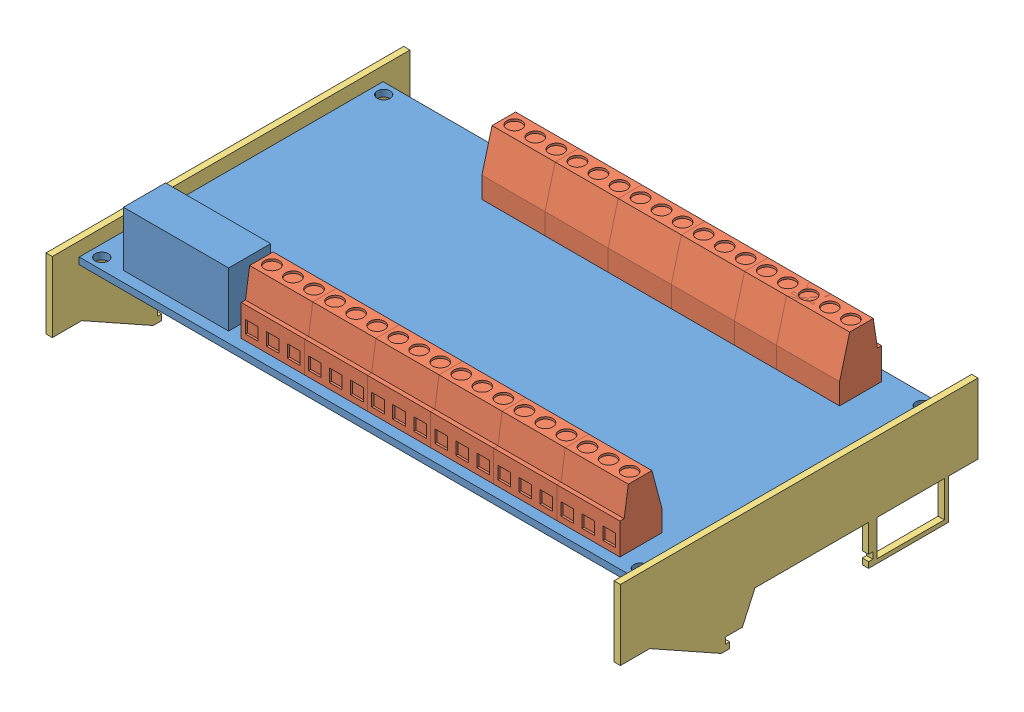
SolidWorks assembly Sanwo_16ch_mosfet_board, configuration Default. Lengths in mm.
Overall size (136.5 36.9 85).
15 component instances, 3 part files, 45 mates.
Components (placement in the parent):
- Sanwo_16ch_mosfet_board-1: Sanwo_16ch_mosfet_board [Default] at origin size (133.5 14.6 72.2)
- screw_terminal_3x_large-1: screw_terminal_3x_large [Default] at (73.5 1.6 -64.7) size (15 18 10)
- screw_terminal_3x_large-2: screw_terminal_3x_large [Default] at (103.5 1.6 -64.7) size (15 18 10)
- screw_terminal_3x_large-3: screw_terminal_3x_large [Default] at (88.5 1.6 -64.7) size (15 18 10)
- screw_terminal_3x_large-4: screw_terminal_3x_large [Default] at (58.5 1.6 -64.7) size (15 18 10)
- screw_terminal_3x_large-5: screw_terminal_3x_large [Default] at (113.5 1.6 -64.7) size (15 18 10)
- screw_terminal_3x_large-6: screw_terminal_3x_large [Default] at (43.5 1.6 -64.7) size (15 18 10)
- screw_terminal_3x_large-7: screw_terminal_3x_large [Default] at (43.5 1.6 -7.5) x (-1 0 0) z (0 0 -1) size (15 18 10)
- screw_terminal_3x_large-8: screw_terminal_3x_large [Default] at (103.5 1.6 -7.5) x (-1 0 0) z (0 0 -1) size (15 18 10)
- screw_terminal_3x_large-9: screw_terminal_3x_large [Default] at (118.5 1.6 -7.5) x (-1 0 0) z (0 0 -1) size (15 18 10)
- screw_terminal_3x_large-10: screw_terminal_3x_large [Default] at (73.5 1.6 -7.5) x (-1 0 0) z (0 0 -1) size (15 18 10)
- screw_terminal_3x_large-11: screw_terminal_3x_large [Default] at (58.5 1.6 -7.5) x (-1 0 0) z (0 0 -1) size (15 18 10)
- screw_terminal_3x_large-12: screw_terminal_3x_large [Default] at (88.5 1.6 -7.5) x (-1 0 0) z (0 0 -1) size (15 18 10)
- Sanwo_16ch_mosfet_board_DIN_rail_support-1: Sanwo_16ch_mosfet_board_DIN_rail_support [Default] at (0 -18.4 -36.1) x (0 0 1) z (-1 0 0) size (85 26.2 1.5)
- Sanwo_16ch_mosfet_board_DIN_rail_support-2: Sanwo_16ch_mosfet_board_DIN_rail_support [Default] at (135 -18.4 -36.1) x (0 0 1) z (-1 0 0) size (85 26.2 1.5)
Mates (geometry in assembly coordinates):
- Coincident12: coincident aligned: plane of screw_terminal_3x_large-7 through (43.5 1.6 -7.5) normal (0 -1 0); plane of screw_terminal_3x_large-8 through (103.5 1.6 -7.5) normal (0 -1 0)
- Coincident13: coincident aligned: plane of screw_terminal_3x_large-7 through (43.5 1.6 -7.5) normal (0 -1 0); plane of screw_terminal_3x_large-9 through (118.5 1.6 -7.5) normal (0 -1 0)
- Coincident14: coincident aligned: plane of screw_terminal_3x_large-7 through (43.5 1.6 -7.5) normal (0 -1 0); plane of screw_terminal_3x_large-10 through (73.5 1.6 -7.5) normal (0 -1 0)
- Coincident15: coincident aligned: plane of screw_terminal_3x_large-7 through (43.5 1.6 -7.5) normal (0 -1 0); plane of screw_terminal_3x_large-11 through (58.5 1.6 -7.5) normal (0 -1 0)
- Coincident16: coincident aligned: plane of screw_terminal_3x_large-7 through (43.5 1.6 -7.5) normal (0 -1 0); plane of screw_terminal_3x_large-12 through (88.5 1.6 -7.5) normal (0 -1 0)
- Coincident17: coincident aligned: plane of screw_terminal_3x_large-6 through (43.5 1.6 -64.7) normal (0 -1 0); plane of screw_terminal_3x_large-7 through (43.5 1.6 -7.5) normal (0 -1 0)
- Coincident18: coincident aligned: plane of screw_terminal_3x_large-5 through (113.5 1.6 -64.7) normal (0 -1 0); plane of screw_terminal_3x_large-7 through (43.5 1.6 -7.5) normal (0 -1 0)
- Coincident19: coincident aligned: plane of screw_terminal_3x_large-4 through (58.5 1.6 -64.7) normal (0 -1 0); plane of screw_terminal_3x_large-7 through (43.5 1.6 -7.5) normal (0 -1 0)
- Coincident20: coincident aligned: plane of screw_terminal_3x_large-3 through (88.5 1.6 -64.7) normal (0 -1 0); plane of screw_terminal_3x_large-7 through (43.5 1.6 -7.5) normal (0 -1 0)
- Coincident21: coincident aligned: plane of screw_terminal_3x_large-2 through (103.5 1.6 -64.7) normal (0 -1 0); plane of screw_terminal_3x_large-7 through (43.5 1.6 -7.5) normal (0 -1 0)
- Coincident22: coincident aligned: plane of screw_terminal_3x_large-1 through (73.5 1.6 -64.7) normal (0 -1 0); plane of screw_terminal_3x_large-7 through (43.5 1.6 -7.5) normal (0 -1 0)
- Coincident23: coincident anti-aligned: plane of Sanwo_16ch_mosfet_board-1 through (0 1.6 0) normal (0 1 0); plane of screw_terminal_3x_large-7 through (43.5 1.6 -7.5) normal (0 -1 0)
- Coincident24: coincident anti-aligned: plane of screw_terminal_3x_large-4 through (51 15.6 -69.7) normal (-1 0 0); plane of screw_terminal_3x_large-6 through (51 15.6 -69.7) normal (1 0 0)
- Coincident25: coincident anti-aligned: plane of screw_terminal_3x_large-1 through (66 15.6 -69.7) normal (-1 0 0); plane of screw_terminal_3x_large-4 through (66 15.6 -69.7) normal (1 0 0)
- Coincident26: coincident anti-aligned: plane of screw_terminal_3x_large-1 through (81 15.6 -69.7) normal (1 0 0); plane of screw_terminal_3x_large-3 through (81 15.6 -69.7) normal (-1 0 0)
- Coincident27: coincident anti-aligned: plane of screw_terminal_3x_large-2 through (96 15.6 -69.7) normal (-1 0 0); plane of screw_terminal_3x_large-3 through (96 15.6 -69.7) normal (1 0 0)
- Distance1: distance = 5 mm anti-aligned: plane of screw_terminal_3x_large-2 through (111 15.6 -69.7) normal (1 0 0); plane of screw_terminal_3x_large-5 through (106 15.6 -69.7) normal (-1 0 0)
- Coincident29: coincident anti-aligned: plane of screw_terminal_3x_large-7 through (51 15.6 -2.5) normal (1 0 0); plane of screw_terminal_3x_large-11 through (51 15.6 -2.5) normal (-1 0 0)
- Coincident30: coincident anti-aligned: plane of screw_terminal_3x_large-10 through (66 15.6 -2.5) normal (-1 0 0); plane of screw_terminal_3x_large-11 through (66 15.6 -2.5) normal (1 0 0)
- Coincident31: coincident anti-aligned: plane of screw_terminal_3x_large-10 through (81 15.6 -2.5) normal (1 0 0); plane of screw_terminal_3x_large-12 through (81 15.6 -2.5) normal (-1 0 0)
- Coincident32: coincident anti-aligned: plane of screw_terminal_3x_large-8 through (96 15.6 -2.5) normal (-1 0 0); plane of screw_terminal_3x_large-12 through (96 15.6 -2.5) normal (1 0 0)
- Coincident33: coincident anti-aligned: plane of screw_terminal_3x_large-8 through (111 15.6 -2.5) normal (1 0 0); plane of screw_terminal_3x_large-9 through (111 15.6 -2.5) normal (-1 0 0)
- Coincident36: coincident aligned: plane of screw_terminal_3x_large-2 through (96 15.6 -59.7) normal (0 0 1); plane of screw_terminal_3x_large-5 through (106 15.6 -59.7) normal (0 0 1)
- Coincident37: coincident aligned: plane of screw_terminal_3x_large-3 through (81 15.6 -59.7) normal (0 0 1); plane of screw_terminal_3x_large-5 through (106 15.6 -59.7) normal (0 0 1)
- Coincident38: coincident aligned: plane of screw_terminal_3x_large-1 through (66 15.6 -59.7) normal (0 0 1); plane of screw_terminal_3x_large-5 through (106 15.6 -59.7) normal (0 0 1)
- Coincident39: coincident aligned: plane of screw_terminal_3x_large-4 through (51 15.6 -59.7) normal (0 0 1); plane of screw_terminal_3x_large-5 through (106 15.6 -59.7) normal (0 0 1)
- Coincident40: coincident aligned: plane of screw_terminal_3x_large-5 through (106 15.6 -59.7) normal (0 0 1); plane of screw_terminal_3x_large-6 through (36 15.6 -59.7) normal (0 0 1)
- Coincident41: coincident aligned: plane of screw_terminal_3x_large-8 through (111 15.6 -12.5) normal (0 0 -1); plane of screw_terminal_3x_large-9 through (126 15.6 -12.5) normal (0 0 -1)
- Coincident42: coincident aligned: plane of screw_terminal_3x_large-9 through (126 15.6 -12.5) normal (0 0 -1); plane of screw_terminal_3x_large-12 through (96 15.6 -12.5) normal (0 0 -1)
- Coincident43: coincident aligned: plane of screw_terminal_3x_large-9 through (126 15.6 -12.5) normal (0 0 -1); plane of screw_terminal_3x_large-10 through (81 15.6 -12.5) normal (0 0 -1)
- Coincident44: coincident aligned: plane of screw_terminal_3x_large-9 through (126 15.6 -12.5) normal (0 0 -1); plane of screw_terminal_3x_large-11 through (66 15.6 -12.5) normal (0 0 -1)
- Coincident45: coincident aligned: plane of screw_terminal_3x_large-7 through (51 15.6 -12.5) normal (0 0 -1); plane of screw_terminal_3x_large-9 through (126 15.6 -12.5) normal (0 0 -1)
- Distance3: distance = 36 mm aligned: plane of Sanwo_16ch_mosfet_board-1 through (0 1.6 0) normal (-1 0 0); plane of screw_terminal_3x_large-7 through (36 15.6 -2.5) normal (-1 0 0)
- Coincident48: coincident aligned: plane of screw_terminal_3x_large-6 through (36 15.6 -69.7) normal (-1 0 0); plane of screw_terminal_3x_large-7 through (36 15.6 -2.5) normal (-1 0 0)
- Distance4: distance = 2.5 mm aligned: plane of Sanwo_16ch_mosfet_board-1 through (0 1.6 0) normal (0 0 1); plane of screw_terminal_3x_large-7 through (51 15.6 -2.5) normal (0 0 1)
- Distance5: distance = 2.5 mm aligned: plane of screw_terminal_3x_large-1 through (66 15.6 -69.7) normal (0 0 -1); plane of Sanwo_16ch_mosfet_board-1 through (0 1.6 -72.2) normal (0 0 -1)
- Coincident49: coincident anti-aligned: plane of Sanwo_16ch_mosfet_board-1 through (0 1.6 0) normal (-1 0 0); plane of Sanwo_16ch_mosfet_board_DIN_rail_support-1 through (0 -18.4 -36.1) normal (1 0 0)
- Coincident50: coincident anti-aligned: plane of Sanwo_16ch_mosfet_board-1 through (133.5 1.6 0) normal (1 0 0); plane of Sanwo_16ch_mosfet_board_DIN_rail_support-2 through (133.5 -18.4 -36.1) normal (-1 0 0)
- Coincident51: coincident aligned: plane of Sanwo_16ch_mosfet_board_DIN_rail_support-1 through (0 -18.4 -36.1) normal (0 0 1); plane of Sanwo_16ch_mosfet_board_DIN_rail_support-2 through (135 -18.4 -36.1) normal (0 0 1)
- Coincident52: coincident aligned: plane of Sanwo_16ch_mosfet_board_DIN_rail_support-1 through (0 -18.4 -36.1) normal (0 1 0); plane of Sanwo_16ch_mosfet_board_DIN_rail_support-2 through (135 -18.4 -36.1) normal (0 1 0)
- Coincident53: coincident aligned: plane of Sanwo_16ch_mosfet_board-1 through (0 0 -36.1) normal (0 0 1); plane of Sanwo_16ch_mosfet_board_DIN_rail_support-2 through (135 -18.4 -36.1) normal (0 0 1)
- Distance6: distance = 3.3 mm aligned: plane of Sanwo_16ch_mosfet_board_DIN_rail_support-1 through (-1.5 4.9 -78.6) normal (0 1 0); plane of Sanwo_16ch_mosfet_board-1 through (0 1.6 0) normal (0 1 0)
- Coincident55: coincident: plane of Sanwo_16ch_mosfet_board-1 through (0 0 -36.1) normal (0 0 1); plane of DIN_rail_35x7.5-1 through (187.6862 -25.9 -36.1) normal (0 0 1)
- Coincident56: coincident: plane of Sanwo_16ch_mosfet_board_DIN_rail_support-2 through (133.5 -18.4 -52.6) normal (0 -1 0); plane of DIN_rail_35x7.5-1 through (-65 -18.4 -53.6) normal (0 1 0)
- Coincident57: coincident aligned: plane of Sanwo_16ch_mosfet_board_DIN_rail_support-2 through (135 -18.4 -36.1) normal (1 0 0); plane of DIN_rail_35x7.5-1 through (135 -25.9 -36.1) normal (1 0 0)
